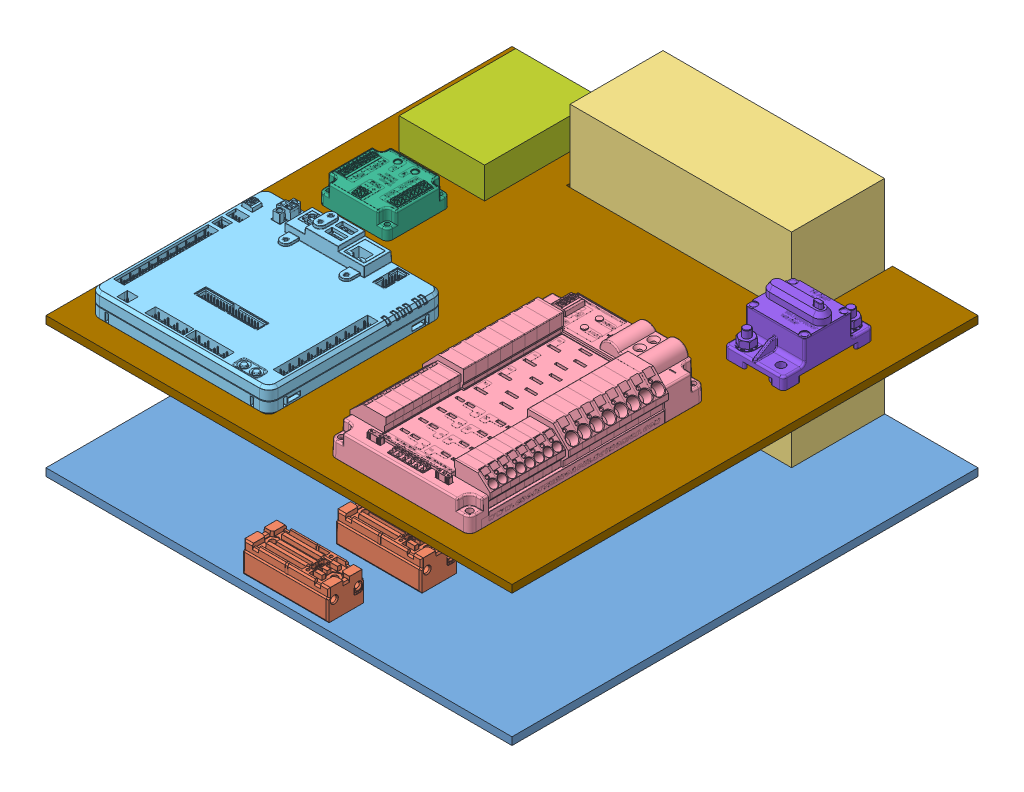
SolidWorks assembly 2boardV2, configuration Default. Lengths in mm.
Overall size (381 173.1 381).
14 component instances, 9 part files, 44 mates.
Components (placement in the parent):
- e-board-1: e-board [Default] at (11.1903 208.843 469.4515) size (381 6.22 381)
- Speed Controller-1: Speed Controller [Default] at (218.8091 230.9035 390.5515) x (0 0 -1) z (0 -1 0) size (30.12 70.11 24.39)
- Speed Controller-2: Speed Controller [Default] at (195.4197 230.9035 288.9515) x (0 0 -1) z (0 -1 0) size (30.12 70.11 24.39)
- Speed Controller-3: Speed Controller [Default] at (195.4197 230.9035 238.1515) x (0 0 -1) z (0 -1 0) size (30.12 70.11 24.39)
- Speed Controller-4: Speed Controller [Default] at (195.4197 230.9035 339.7515) x (0 0 -1) z (0 -1 0) size (30.12 70.11 24.39)
- Battery-1: Battery [Default] at (134.8883 215.066 88.7055) x (0 0 1) z (-1 0 0) size (75.95 166.88 181.1)
- PDP-1: PDP [Default] at (283.1225 329.5692 360.3582) x (0 0 1) z (-1 0 0) size (192.68 36.15 120.93)
- Roborio-1: Roborio [Default] at (102.9515 332.541 380.5718) x (1 0 0) z (0 1 0) size (146.27 143.19 36.83)
- VRM-1: VRM [Default] at (71.5666 329.9949 250.7562) size (56.39 19.92 51.56)
- radio b;ock-1: radio b;ock [Default] at (39.5883 322.889 209.1015) size (69.85 25.4 95.25)
- Breaker-1: Breaker [Default] at (342.6603 327.715 185.3854) x (0 0 -1) z (1 0 0) size (73.72 42.2 48.95)
- board with battery cut out-1: board with battery cut out [Default] at (11.1903 316.666 469.4515) size (381 6.22 381)
- Speed Controller-5: Speed Controller [Default] at (201.7697 230.9035 449.4587) x (0 0 -1) z (0 -1 0) size (30.12 70.11 24.39)
- Speed Controller-6: Speed Controller [Default] at (194.5497 230.9035 199.6152) x (0 0 -1) z (0 -1 0) size (30.12 70.11 24.39)
Mates (geometry in assembly coordinates):
- Coincident1: coincident anti-aligned: plane of e-board-1 through (11.1903 215.066 469.4515) normal (0 1 0); plane of Speed Controller-1 through (183.8841 215.066 375.4892) normal (0 -1 0)
- Perpendicular2: perpendicular: plane of e-board-1 through (392.1903 215.066 469.4515) normal (1 0 0); plane of Speed Controller-1 through (231.0297 237.5535 390.3115) normal (0 0 -1)
- Distance1: distance = 76.2 mm: plane of Speed Controller-1 through (231.4297 237.5535 393.2515) normal (0 0 1); line of e-board-1 through (11.1903 208.843 469.4515) axis (1 0 0)
- Distance2: distance = 222.25 mm: line of Speed Controller-1 through (232.2997 237.5535 392.8515) axis (0 0 1); line of e-board-1 through (11.1903 215.066 88.4515) axis (0 0 1)
- Coincident5: coincident anti-aligned: plane of e-board-1 through (11.1903 215.066 469.4515) normal (0 1 0); plane of Speed Controller-4 through (160.4947 215.066 324.6892) normal (0 -1 0)
- Coincident6: coincident anti-aligned: plane of e-board-1 through (11.1903 215.066 469.4515) normal (0 1 0); plane of Speed Controller-3 through (160.4947 215.066 223.0892) normal (0 -1 0)
- Coincident7: coincident anti-aligned: plane of e-board-1 through (11.1903 215.066 469.4515) normal (0 1 0); plane of Speed Controller-2 through (160.4947 215.066 273.8892) normal (0 -1 0)
- Perpendicular3: perpendicular: plane of e-board-1 through (392.1903 215.066 469.4515) normal (1 0 0); plane of Speed Controller-4 through (207.6403 237.5535 339.5115) normal (0 0 -1)
- Perpendicular5: perpendicular: plane of e-board-1 through (392.1903 215.066 469.4515) normal (1 0 0); plane of Speed Controller-3 through (207.6403 237.5535 235.3715) normal (0 0 -1)
- Perpendicular6: perpendicular: plane of e-board-1 through (392.1903 215.066 469.4515) normal (1 0 0); plane of Speed Controller-2 through (207.6403 237.5535 286.1715) normal (0 0 -1)
- Distance3: distance = 184.15 mm: plane of Speed Controller-4 through (208.0403 237.5535 342.0515) normal (1 0 0); line of e-board-1 through (392.1903 215.066 469.4515) axis (0 0 -1)
- Distance5: distance = 184.15 mm aligned: plane of Speed Controller-2 through (208.0403 237.5535 289.9815) normal (1 0 0); plane of e-board-1 through (392.1903 215.066 469.4515) normal (1 0 0)
- Distance6: distance = 127 mm aligned: plane of Speed Controller-4 through (209.3103 237.5535 342.4515) normal (0 0 1); plane of e-board-1 through (11.1903 215.066 469.4515) normal (0 0 1)
- Distance7: distance = 177.8 mm aligned: plane of Speed Controller-2 through (208.0403 237.5535 291.6515) normal (0 0 1); plane of e-board-1 through (11.1903 215.066 469.4515) normal (0 0 1)
- Distance8: distance = 184.15 mm: plane of Speed Controller-3 through (208.0403 237.5535 240.4515) normal (1 0 0); line of e-board-1 through (392.1903 215.066 469.4515) axis (0 0 -1)
- Distance9: distance = 228.6 mm aligned: plane of Speed Controller-3 through (208.0403 237.5535 240.8515) normal (0 0 1); plane of e-board-1 through (11.1903 215.066 469.4515) normal (0 0 1)
- Coincident19: coincident anti-aligned: plane of e-board-1 through (11.1903 215.066 469.4515) normal (0 1 0); plane of Battery-1 through (134.8883 215.066 88.7055) normal (0 -1 0)
- Distance11: distance = 76.2 mm aligned: plane of Battery-1 through (315.9903 381.944 88.7055) normal (1 0 0); plane of e-board-1 through (392.1903 215.066 469.4515) normal (1 0 0)
- Coincident39: coincident aligned: plane of e-board-1 through (392.1903 215.066 469.4515) normal (1 0 0); plane of board with battery cut out-1 through (392.1903 284.789 469.4515) normal (1 0 0)
- Coincident40: coincident aligned: plane of e-board-1 through (11.1903 215.066 469.4515) normal (0 0 1); plane of board with battery cut out-1 through (11.1903 284.789 469.4515) normal (0 0 1)
- Distance25: distance = 101.6 mm anti-aligned: plane of e-board-1 through (11.1903 215.066 469.4515) normal (0 1 0); plane of board with battery cut out-1 through (11.1903 316.666 469.4515) normal (0 -1 0)
- Coincident42: coincident anti-aligned: plane of PDP-1 through (225.7185 284.789 452.3824) normal (0 -1 0); plane of board with battery cut out-1 through (11.1903 284.789 469.4515) normal (0 1 0)
- Coincident43: coincident anti-aligned: plane of Breaker-1 through (363.031 284.789 215.9079) normal (0 -1 0); plane of board with battery cut out-1 through (11.1903 284.789 469.4515) normal (0 1 0)
- Coincident44: coincident anti-aligned: plane of radio b;ock-1 through (39.5883 284.789 209.1015) normal (0 -1 0); plane of board with battery cut out-1 through (11.1903 284.789 469.4515) normal (0 1 0)
- Coincident45: coincident anti-aligned: plane of VRM-1 through (94.911 284.789 231.209) normal (0 -1 0); plane of board with battery cut out-1 through (11.1903 284.789 469.4515) normal (0 1 0)
- Coincident47: coincident: plane of Roborio-1 through (29.4396 284.789 452.5385) normal (0 1 0); line of board with battery cut out-1 through (11.1903 284.789 469.4515) axis (1 0 0)
- Distance26: distance = 95.25 mm aligned: plane of PDP-1 through (296.9403 345.5314 444.0515) normal (1 0 0); plane of board with battery cut out-1 through (392.1903 322.889 469.4515) normal (1 0 0)
- Distance27: distance = 25.4 mm aligned: plane of PDP-1 through (294.2603 345.5314 444.0515) normal (0 0 1); plane of board with battery cut out-1 through (11.1903 322.889 469.4515) normal (0 0 1)
- Distance28: distance = 25.4 mm aligned: plane of Roborio-1 through (118.1915 342.9084 444.0515) normal (0 0 1); plane of board with battery cut out-1 through (11.1903 322.889 469.4515) normal (0 0 1)
- Distance29: distance = 63.5 mm aligned: plane of Roborio-1 through (74.6903 342.9084 380.5718) normal (-1 0 0); plane of board with battery cut out-1 through (11.1903 322.889 469.4515) normal (-1 0 0)
- Distance30: distance = 38.1 mm: plane of VRM-1 through (49.2903 342.7882 263.5715) normal (-1 0 0); line of board with battery cut out-1 through (11.1903 322.889 88.4515) axis (0 0 1)
- Distance31: distance = 203.2 mm: plane of board with battery cut out-1 through (11.1903 322.889 469.4515) normal (0 0 1); line of VRM-1 through (49.2903 342.7882 266.2515) axis (1 0 0)
- Distance32: distance = 25.4 mm: plane of radio b;ock-1 through (39.5883 348.289 113.8515) normal (0 0 -1); moEndPointRef_w of board with battery cut out-1
- Distance33: distance = 38.1 mm: moEndPointRef_w of radio b;ock-1; line of board with battery cut out-1 through (11.1903 322.889 88.4515) axis (0 0 1)
- Distance34: distance = 25.4 mm aligned: plane of Breaker-1 through (366.7903 330.255 185.3854) normal (1 0 0); plane of board with battery cut out-1 through (392.1903 322.889 469.4515) normal (1 0 0)
- Distance35: distance = 95.25 mm: plane of Breaker-1 through (357.1383 358.688 183.7015) normal (0 0 -1); line of board with battery cut out-1 through (392.1903 322.889 88.4515) axis (-1 0 0)
- Parallel4: parallel aligned: plane of radio b;ock-1 through (39.5883 310.189 113.8515) normal (0 0 -1); plane of board with battery cut out-1 through (11.1903 284.789 88.4515) normal (0 0 -1)
- Coincident60: coincident anti-aligned: plane of Battery-1 through (134.8883 381.944 164.6515) normal (0 0 1); plane of board with battery cut out-1 through (131.8403 30.789 164.6515) normal (0 0 -1)
- Coincident61: coincident: plane of e-board-1 through (11.1903 215.066 469.4515) normal (0 1 0); plane of Speed Controller-5 through (166.8447 215.066 434.3963) normal (0 -1 0)
- Perpendicular8: perpendicular: line of e-board-1 through (11.1903 215.066 88.4515) axis (0 0 1); plane of Speed Controller-5 through (213.9903 237.5535 447.9487) normal (0 0 -1)
- Distance36: distance = 177.8 mm: plane of Speed Controller-5 through (214.3903 237.5535 451.7587) normal (1 0 0); line of e-board-1 through (392.1903 215.066 469.4515) axis (0 0 -1)
- Coincident65: coincident: plane of e-board-1 through (11.1903 215.066 469.4515) normal (0 1 0); plane of Speed Controller-6 through (140.5747 215.066 184.5529) normal (0 -1 0)
- Perpendicular9: perpendicular: plane of e-board-1 through (392.1903 215.066 469.4515) normal (1 0 0); plane of Speed Controller-6 through (187.7203 237.5535 200.6452) normal (0 0 -1)
- Distance37: distance = 196.85 mm: plane of Speed Controller-6 through (208.0403 237.5535 197.2352) normal (-1 0 0); line of e-board-1 through (11.1903 215.066 88.4515) axis (0 0 1)
